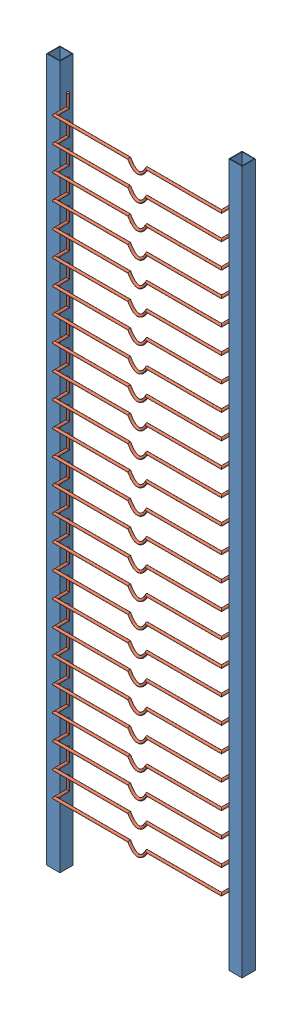
SolidWorks assembly side_assembly, configuration Default. Lengths in mm.
Overall size (527.68 1898.65 55.7).
26 component instances, 2 part files, 5 mates.
Components (placement in the parent):
- side-1: side [Default] at (-485.354 -800.922 1914.779) size (527.68 1898.65 35.56)
- cross_bar-2: cross_bar [Default] at (-448.2065 -580.3312 1897.771) size (456.56 60.39 42.04)
- cross_bar-3: cross_bar [Default] at (-448.2065 -513.7832 1897.771) size (456.56 60.39 42.04)
- cross_bar-4: cross_bar [Default] at (-448.2065 -447.2352 1897.771) size (456.56 60.39 42.04)
- cross_bar-5: cross_bar [Default] at (-448.2065 -380.6872 1897.771) size (456.56 60.39 42.04)
- cross_bar-6: cross_bar [Default] at (-448.2065 -314.1392 1897.771) size (456.56 60.39 42.04)
- cross_bar-7: cross_bar [Default] at (-448.2065 -247.5912 1897.771) size (456.56 60.39 42.04)
- cross_bar-8: cross_bar [Default] at (-448.2065 -181.0432 1897.771) size (456.56 60.39 42.04)
- cross_bar-9: cross_bar [Default] at (-448.2065 -114.4952 1897.771) size (456.56 60.39 42.04)
- cross_bar-10: cross_bar [Default] at (-448.2065 -47.9472 1897.771) size (456.56 60.39 42.04)
- cross_bar-11: cross_bar [Default] at (-448.2065 18.6008 1897.771) size (456.56 60.39 42.04)
- cross_bar-12: cross_bar [Default] at (-448.2065 85.1488 1897.771) size (456.56 60.39 42.04)
- cross_bar-13: cross_bar [Default] at (-448.2065 151.6968 1897.771) size (456.56 60.39 42.04)
- cross_bar-14: cross_bar [Default] at (-448.2065 218.2448 1897.771) size (456.56 60.39 42.04)
- cross_bar-15: cross_bar [Default] at (-448.2065 284.7928 1897.771) size (456.56 60.39 42.04)
- cross_bar-16: cross_bar [Default] at (-448.2065 351.3408 1897.771) size (456.56 60.39 42.04)
- cross_bar-17: cross_bar [Default] at (-448.2065 417.8888 1897.771) size (456.56 60.39 42.04)
- cross_bar-18: cross_bar [Default] at (-448.2065 484.4368 1897.771) size (456.56 60.39 42.04)
- cross_bar-19: cross_bar [Default] at (-448.2065 550.9848 1897.771) size (456.56 60.39 42.04)
- cross_bar-20: cross_bar [Default] at (-448.2065 617.5328 1897.771) size (456.56 60.39 42.04)
- cross_bar-21: cross_bar [Default] at (-448.2065 684.0808 1897.771) size (456.56 60.39 42.04)
- cross_bar-22: cross_bar [Default] at (-448.2065 750.6288 1897.771) size (456.56 60.39 42.04)
- cross_bar-23: cross_bar [Default] at (-448.2065 817.1768 1897.771) size (456.56 60.39 42.04)
- cross_bar-24: cross_bar [Default] at (-448.2065 883.7248 1897.771) size (456.56 60.39 42.04)
- cross_bar-25: cross_bar [Default] at (-448.2065 950.2728 1897.771) size (456.56 60.39 42.04)
- cross_bar-26: cross_bar [Default] at (-448.2065 1016.8208 1897.771) size (456.56 60.39 42.04)
Mates (geometry in assembly coordinates):
- Tangent1: tangent anti-aligned: plane of side-1 through (5.12 1097.728 1916.43) normal (-1 0 0); cylinder of cross_bar-2 through (1.8815 -615.8912 1940.5557) axis (0 0 -1) radius 3.2385
- Tangent2: tangent anti-aligned: plane of side-1 through (-451.445 1097.728 1916.43) normal (1 0 0); cylinder of cross_bar-2 through (-448.2065 -615.8912 1894.1087) axis (0 0 1) radius 3.2385
- Distance1: distance = 182.5625 mm: cylinder of cross_bar-2 through (-201.2226 -615.8912 1933.331) axis (1 0 0) radius 3.2385; line of side-1 through (5.12 -800.922 1916.43) axis (1 0 0)
- Perpendicular1: perpendicular: plane of side-1 through (-487.005 1097.728 1880.87) normal (0 0 -1); plane of cross_bar-2 through (-448.2065 -580.3312 1897.771) normal (0 1 0)
- Distance3: distance = 13.97 mm: line of side-1 through (-451.445 1097.728 1880.87) axis (0 -1 0); cylinder of cross_bar-2 through (-448.2065 -580.3312 1897.771) axis (0 -1 0) radius 3.2385
